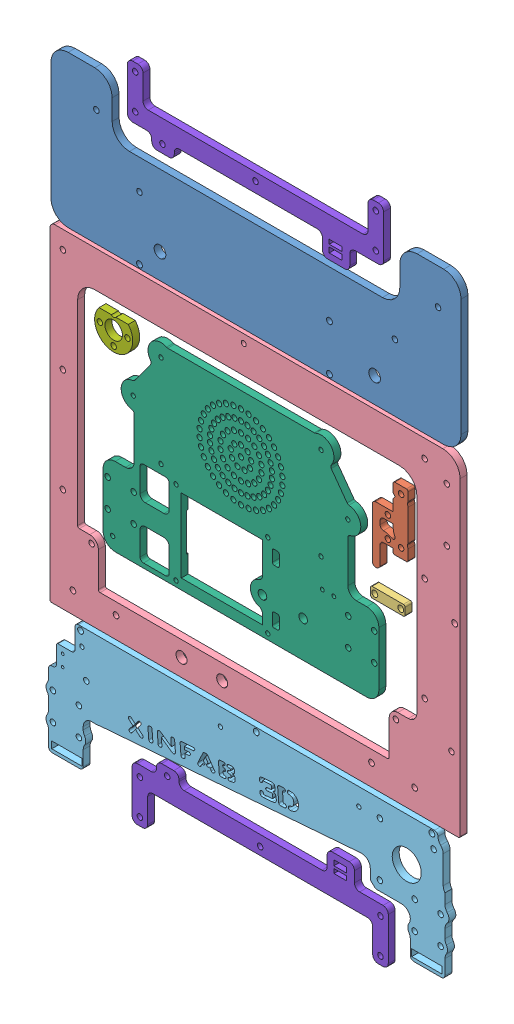
SolidWorks assembly To CNC Complete, configuration Default. Lengths in mm.
Overall size (239.82 380.7 4).
9 component instances, 8 part files, 13 mates.
Components (placement in the parent):
- FOOT-1: FOOT [Default] at (54.1859 440.8719 192.0753) size (237 87.75 4)
- Extruder stopper2-1: Extruder stopper2 [Valor predeterminado] at (143.043 28.8794 192.0753) x (0 -1 0) z (0 0 1) size (48.08 20.7 4)
- Hotend bracket-1: Hotend bracket [Valor predeterminado] at (161.7509 -51.1611 58.7096) size (19.93 5.9 4)
- Mini CF Main Frame external3-1: Mini CF Main Frame external3 [Valor predeterminado] at (13.031 27.1883 192.0753) size (237 190 4)
- Mini CF X Bridge 4-1: Mini CF X Bridge 4 [Valor predeterminado] at (59.5438 -204.1775 192.0753) size (232.81 71.67 4)
- Mini CF Y table support.SLDASM1-1: Mini CF Y table support.SLDASM1 [Default] at (-43.3476 -96.4768 192.0753) size (159.38 117.99 4)
- Mini CF Z nut atachment-1: Mini CF Z nut atachment [Valor predeterminado] at (-121.5312 346.0837 192.0753) size (22 18.05 4)
- TABLE2-1: TABLE2 [Valor predeterminado] at (69.4328 389.1585 192.0753) size (148 42.68 4)
- TABLE2-2: TABLE2 [Valor predeterminado] at (72.1436 -403.0716 196.0753) x (1 0 0) z (0 0 -1) size (148 42.68 4)
Mates (geometry in assembly coordinates):
- Coincident1: coincident aligned: plane of FOOT-1 through (54.1859 440.8719 196.0753) normal (0 0 1); plane of Mini CF Main Frame external3-1 through (-57.7254 69.0727 196.0753) normal (0 0 1)
- Coincident2: coincident aligned: plane of FOOT-1 through (54.1859 440.8719 196.0753) normal (0 0 1); plane of Mini CF Y table support.SLDASM1-1 through (-43.3476 -96.4768 196.0753) normal (0 0 1)
- Coincident3: coincident aligned: plane of FOOT-1 through (54.1859 440.8719 196.0753) normal (0 0 1); plane of Extruder stopper2-1 through (143.043 28.8794 196.0753) normal (0 0 1)
- Coincident4: coincident aligned: plane of FOOT-1 through (54.1859 440.8719 196.0753) normal (0 0 1); plane of Mini CF Z nut atachment-1 through (-17.8846 43.3177 196.0753) normal (0 0 1)
- Coincident5: coincident aligned: plane of FOOT-1 through (54.1859 440.8719 196.0753) normal (0 0 1); plane of Hotend bracket-1 through (161.7509 -51.1611 196.0753) normal (0 0 1)
- Coincident6: coincident aligned: plane of FOOT-1 through (54.1859 440.8719 196.0753) normal (0 0 1); plane of Mini CF X Bridge 4-1 through (59.5438 -204.1775 196.0753) normal (0 0 1)
- Coincident7: coincident aligned: plane of Mini CF Main Frame external3-1 through (-57.7254 69.0727 196.0753) normal (0 0 1); plane of Mini CF Y table support.SLDASM1-1 through (-43.3476 -96.4768 196.0753) normal (0 0 1)
- Coincident8: coincident aligned: plane of Mini CF Main Frame external3-1 through (-57.7254 69.0727 196.0753) normal (0 0 1); plane of Mini CF Z nut atachment-1 through (-17.8846 43.3177 196.0753) normal (0 0 1)
- Coincident9: coincident aligned: plane of Mini CF Main Frame external3-1 through (-57.7254 69.0727 196.0753) normal (0 0 1); plane of Mini CF Y table support.SLDASM1-1 through (-43.3476 -96.4768 196.0753) normal (0 0 1)
- Coincident10: coincident aligned: plane of Mini CF X Bridge 4-1 through (59.5438 -204.1775 192.0753) normal (0 0 -1); plane of TABLE2-2 through (-24.3056 -169.7171 192.0753) normal (0 0 -1)
- Coincident11: coincident aligned: plane of FOOT-1 through (54.1859 440.8719 192.0753) normal (0 0 -1); plane of TABLE2-1 through (-27.0164 155.804 192.0753) normal (0 0 -1)
- Parallel1: parallel anti-aligned: plane of Extruder stopper2-1 through (152.243 28.8794 196.0753) normal (1 0 0); plane of Mini CF Main Frame external3-1 through (157.2746 -51.9273 196.0753) normal (-1 0 0)
- Parallel2: parallel anti-aligned: plane of Mini CF Main Frame external3-1 through (181.2746 -110.9273 196.0753) normal (0 -1 0); plane of TABLE2-2 through (22.8483 -166.7171 192.0753) normal (0 1 0)
